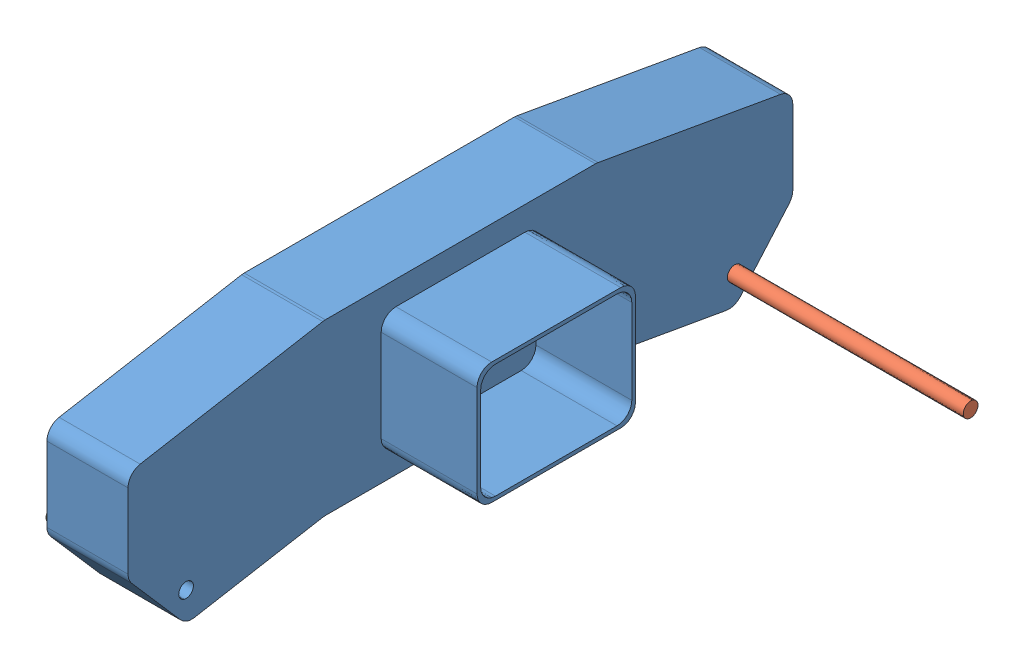
SolidWorks assembly AssemGearbox_Motor, configuration Default. Lengths in mm.
Overall size (50 26.13 90.18).
3 component instances, 3 part files, 4 mates.
Components (placement in the parent):
- Rose - Motor_body-1: Rose - Motor_body [Default] at (19.8097 56.2296 70.3008) size (24 26.13 90.18)
- Rose - Wheel_rod_lo-1: Rose - Wheel_rod_lo [Default] at (12.8097 42.2283 36.335) size (50 2 2)
- Rose - Wheel_rod_sh-1: Rose - Wheel_rod_sh [Default] at (12.8097 42.2283 110.7577) size (10 2 2)
Mates (geometry in assembly coordinates):
- Concentric1: concentric aligned: cylinder of Rose - Motor_body-1 through (30.8097 42.2283 110.7577) axis (-1 0 0) radius 1; cylinder of Rose - Wheel_rod_sh-1 through (22.8097 42.2283 110.7577) axis (-1 0 0) radius 1
- Distance1: distance = 7 mm aligned: plane of Rose - Wheel_rod_sh-1 through (12.8097 42.2283 110.7577) normal (-1 0 0); plane of Rose - Motor_body-1 through (19.8097 56.2296 70.3008) normal (-1 0 0)
- Concentric2: concentric aligned: cylinder of Rose - Motor_body-1 through (30.8097 42.2283 36.335) axis (-1 0 0) radius 1; cylinder of Rose - Wheel_rod_lo-1 through (62.8097 42.2283 36.335) axis (-1 0 0) radius 1
- Distance2: distance = 7 mm aligned: plane of Rose - Wheel_rod_lo-1 through (12.8097 42.2283 36.335) normal (-1 0 0); plane of Rose - Motor_body-1 through (19.8097 56.2296 70.3008) normal (-1 0 0)
